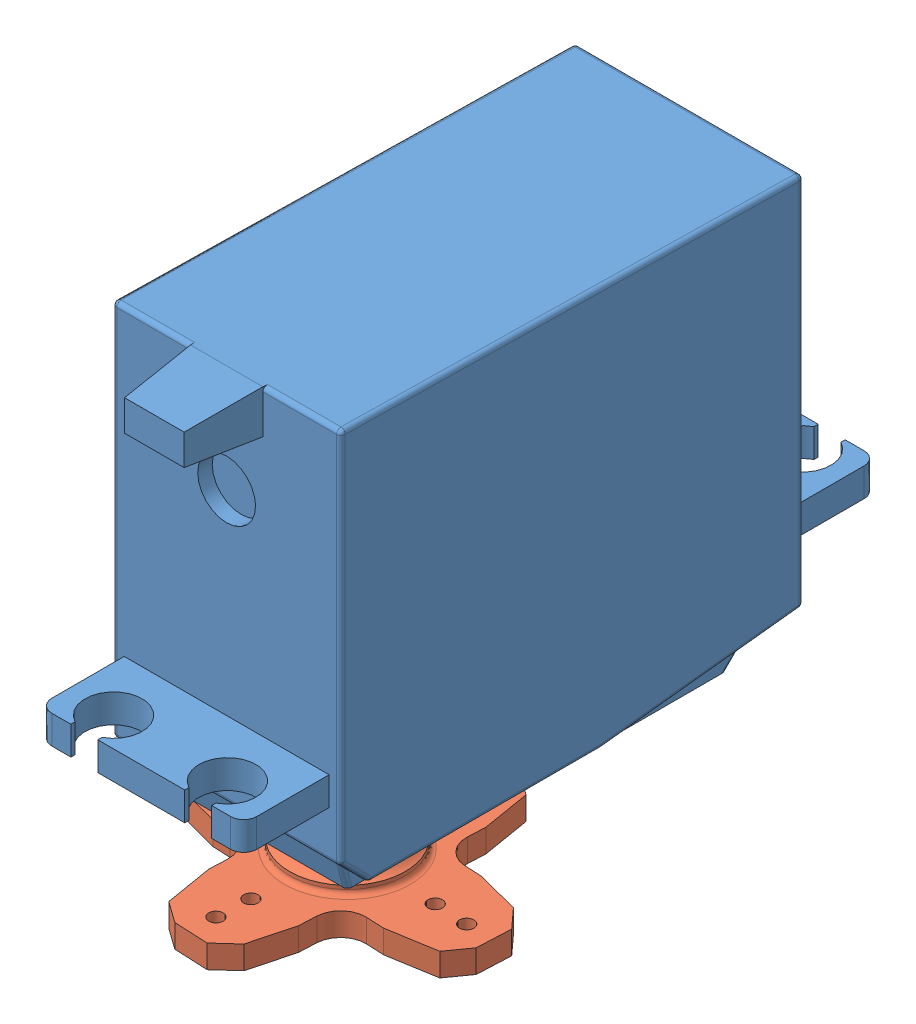
SolidWorks assembly 900-00360 - Parallax 360 Deg Servo, configuration Trimmed Horn. Lengths in mm.
Overall size (27.84 44.65 55.64).
2 component instances, 2 part files, 5 mates.
Components (placement in the parent):
- Parallax-Servo_DUMMY-1: Parallax-Servo_DUMMY [Default] at origin
- Parallax-Servo-Horn-1: Parallax-Servo-Horn [Trimmed] at (0 -5.5372 12.9794) x (-0.998896 0 -0.046981) z (0 -1 0) size (26.62 26.62 6.17)
Mates (geometry in assembly coordinates):
- Coincident1: coincident aligned: plane of Parallax-Servo_DUMMY-1 through (0 0 0) normal (1 0 0); plane of assembly through (0 0 0) normal (1 0 0)
- Coincident2: coincident aligned: plane of Parallax-Servo_DUMMY-1 through (0 0 0) normal (0 1 0); plane of assembly through (0 0 0) normal (0 1 0)
- Coincident3: coincident aligned: plane of Parallax-Servo_DUMMY-1 through (0 0 0) normal (0 0 1); plane of assembly through (0 0 0) normal (0 0 1)
- Concentric1: concentric anti-aligned: cylinder of Parallax-Servo_DUMMY-1 through (0 -4.191 12.9794) axis (0 1 0) radius 2.9845; cylinder of Parallax-Servo-Horn-1 through (0 -4.9022 12.9794) axis (0 -1 0) radius 2.9845
- Coincident4: coincident anti-aligned: plane of Parallax-Servo_DUMMY-1 through (0 -4.191 12.9794) normal (0 -1 0); plane of Parallax-Servo-Horn-1 through (0 -4.191 12.9794) normal (0 1 0)
